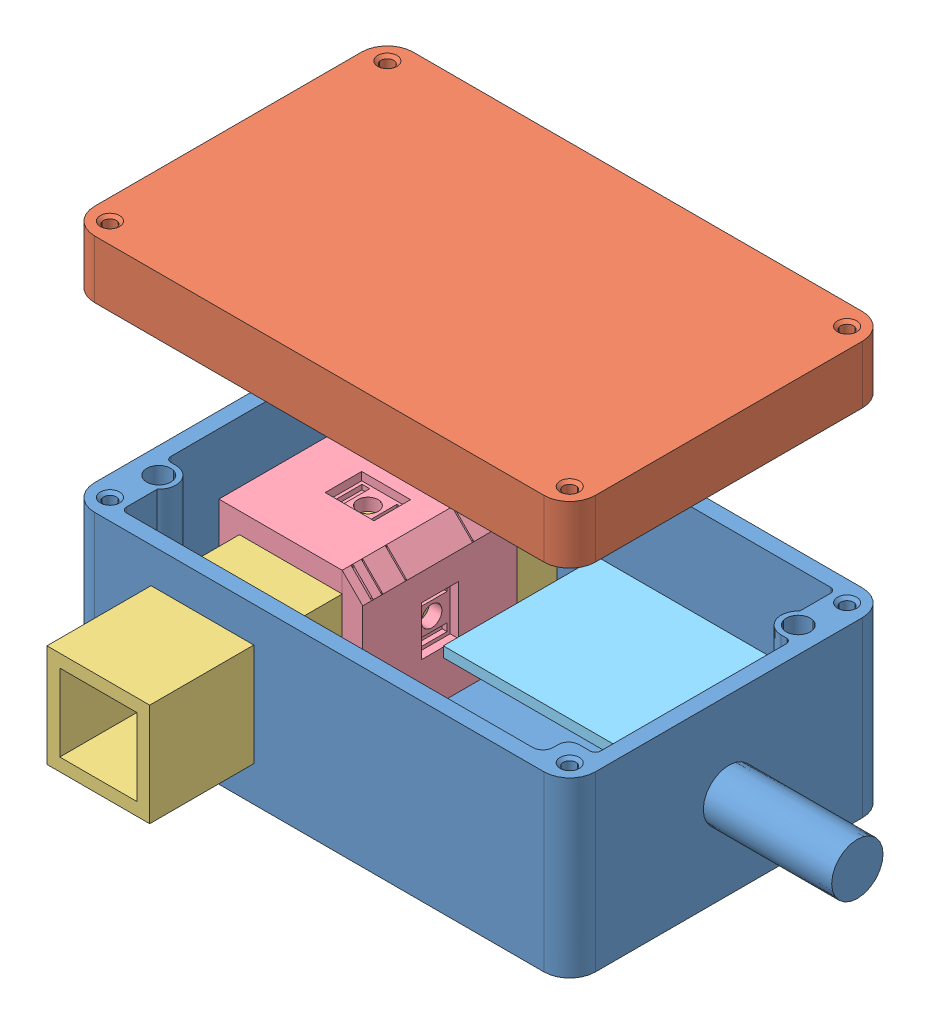
SolidWorks assembly Metal Box Assembly, configuration Default. Lengths in mm.
Overall size (155.58 102.05 127).
7 component instances, 6 part files, 9 mates.
Components (placement in the parent):
- Metal Box-1: Metal Box [Default] at (-5.1078 31.5756 136.72) size (155.57 42.86 78.74)
- Metal Box Top-1: Metal Box Top [Default] at (-5.1078 119.3363 136.72) size (123.83 14.29 78.74)
- Tube-1: Tube [Default] at (27.9122 53.0069 35.4555) size (25.4 25.4 127)
- 3D Printed Part_notched_FINAL-1: 3D Printed Part_notched_FINAL [Default] at (15.2122 25.0669 83.1158) x (1 0 0) z (0 -1 0) size (35.56 38.1 35.56)
- 3D Printed Part_notched_FINAL-2: 3D Printed Part_notched_FINAL [Default] at (40.6122 80.9469 83.1158) x (-1 0 0) z (0 1 0) size (35.56 38.1 35.56)
- Part1^Metal Box Assembly-1: Part1^Metal Box Assembly [Default] at origin (virtual)
- PCB-1: PCB [Default] at (109.4581 50.8056 110.0938) size (50.8 2.54 38.1)
Mates (geometry in assembly coordinates):
- Coincident1: coincident aligned: plane of Metal Box-1 through (118.7172 74.4381 130.37) normal (1 0 0); plane of Metal Box Top-1 through (118.7172 133.6238 130.37) normal (1 0 0)
- Coincident2: coincident aligned: plane of Metal Box-1 through (1.2422 74.4381 136.72) normal (0 0 1); plane of Metal Box Top-1 through (1.2422 133.6238 136.72) normal (0 0 1)
- Coincident3: coincident anti-aligned: plane of Metal Box-1 through (40.6122 65.7069 136.72) normal (-1 0 0); plane of Tube-1 through (40.6122 40.3069 162.4555) normal (1 0 0)
- Coincident4: coincident anti-aligned: plane of Metal Box-1 through (40.6122 40.3069 136.72) normal (0 1 0); plane of Tube-1 through (40.6122 40.3069 162.4555) normal (0 -1 0)
- Coincident9: coincident anti-aligned: plane of 3D Printed Part_notched_FINAL-1 through (15.2122 65.7069 76.7658) normal (0 -1 0); plane of 3D Printed Part_notched_FINAL-2 through (45.6922 65.7069 87.3878) normal (0 1 0)
- Coincident10: coincident aligned: plane of 3D Printed Part_notched_FINAL-1 through (15.2122 65.7069 114.8658) normal (0 0 1); plane of 3D Printed Part_notched_FINAL-2 through (40.6122 40.3069 114.8658) normal (0 0 1)
- Coincident11: coincident: plane of 3D Printed Part_notched_FINAL-1 through (10.1322 35.2269 76.7658) normal (-1 0 0); line of 3D Printed Part_notched_FINAL-2 through (10.1322 40.3069 110.1458) axis (0 0 1)
- Coincident13: coincident anti-aligned: plane of Tube-1 through (40.6122 40.3069 162.4555) normal (0 -1 0); plane of 3D Printed Part_notched_FINAL-2 through (40.6122 40.3069 76.7658) normal (0 1 0)
- Coincident14: coincident anti-aligned: plane of Tube-1 through (15.2122 40.3069 162.4555) normal (-1 0 0); plane of 3D Printed Part_notched_FINAL-1 through (15.2122 65.7069 76.7658) normal (1 0 0)
